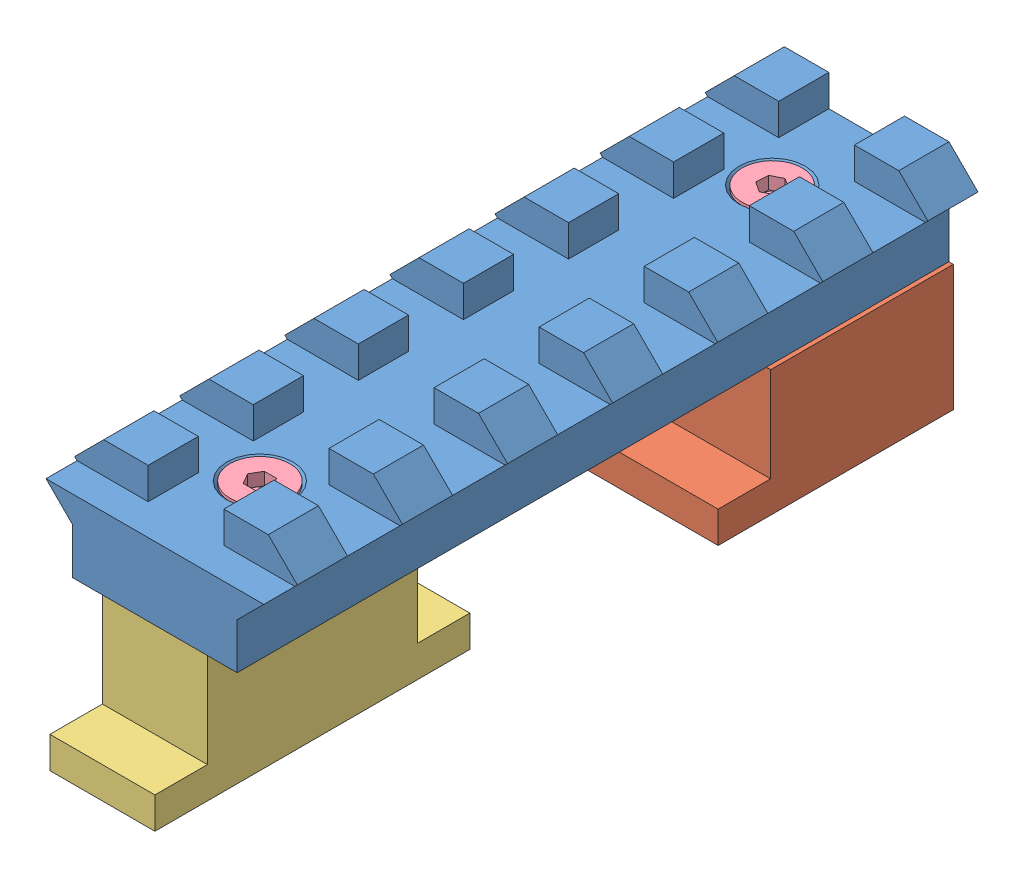
SolidWorks assembly Baugruppe1, configuration Standard. Lengths in mm.
Overall size (21.21 21.9 72.8).
5 component instances, 4 part files, 10 mates.
Components (placement in the parent):
- Rail-3: Rail [Standard] at (-4.1271 5.1584 0) size (21.21 9.9 67.8)
- flip_back-3: flip_back [Standard] at (-4.1271 -4.7457 0) x (0 0 1) z (-1 0 0) size (22.4 12 16.5)
- flip_front-1: flip_front [Standard] at (-4.1271 -4.7457 57.8) x (0 0 -1) z (1 0 0) size (30 12 10)
- Socket Countersunk Head Screw_DIN-2: Socket Countersunk Head Screw_DIN [DIN 7991 - M3 x 12 --- 8.8S] at (-4.1271 2.1584 57.8) x (0 -1 0) z (0 0 1) size (12 5.7 5.7)
- Socket Countersunk Head Screw_DIN-3: Socket Countersunk Head Screw_DIN [DIN 7991 - M3 x 12 --- 8.8S] at (-4.1271 2.1584 9) x (0 -1 0) z (-0.546944 0 0.837169) size (12 5.7 5.7)
Mates (geometry in assembly coordinates):
- Deckungsgleich6: coincident: moEndPointRef_w of Rail-3; moEndPointRef_w of flip_back-3
- Deckungsgleich7: coincident anti-aligned: plane of Rail-3 through (-11.963 -4.7457 67.8) normal (0 -1 0); plane of flip_back-3 through (-12.3771 -4.7457 0) normal (0 1 0)
- Deckungsgleich8: coincident anti-aligned: line of Rail-3 through (-11.963 -4.7457 0) axis (1 0 0); line of flip_back-3 through (4.1229 -4.7457 0) axis (-1 0 0)
- Deckungsgleich9: coincident aligned: plane of Rail-3 through (-4.1271 12.9943 67.8) normal (0 0 1); plane of flip_front-1 through (0.8729 -13.7457 67.8) normal (0 0 1)
- Deckungsgleich10: coincident: moEndPointRef_w of flip_front-1; moEndPointRef_w of Rail-3
- Deckungsgleich11: coincident anti-aligned: plane of Rail-3 through (-11.963 -4.7457 67.8) normal (0 -1 0); plane of flip_front-1 through (0.8729 -4.7457 72.8) normal (0 1 0)
- Konzentrisch1: concentric aligned: cone of Rail-3 through (-4.1271 2.1584 9) axis (0 -1 0); cone of Socket Countersunk Head Screw_DIN-3 through (-4.1271 1.8084 9) axis (0 -1 0)
- Deckungsgleich12: coincident aligned: plane of Rail-3 through (-7.7316 2.1584 67.8) normal (0 1 0); plane of Socket Countersunk Head Screw_DIN-3 through (-4.1271 2.1584 9) normal (0 1 0)
- Konzentrisch3: concentric aligned: cone of Rail-3 through (-4.1271 2.1612 57.8) axis (0 -1 0); cone of Socket Countersunk Head Screw_DIN-2 through (-4.1271 1.8084 57.8) axis (0 -1 0)
- Deckungsgleich13: coincident aligned: plane of Rail-3 through (-7.7316 2.1584 67.8) normal (0 1 0); plane of Socket Countersunk Head Screw_DIN-2 through (-4.1271 2.1584 57.8) normal (0 1 0)
